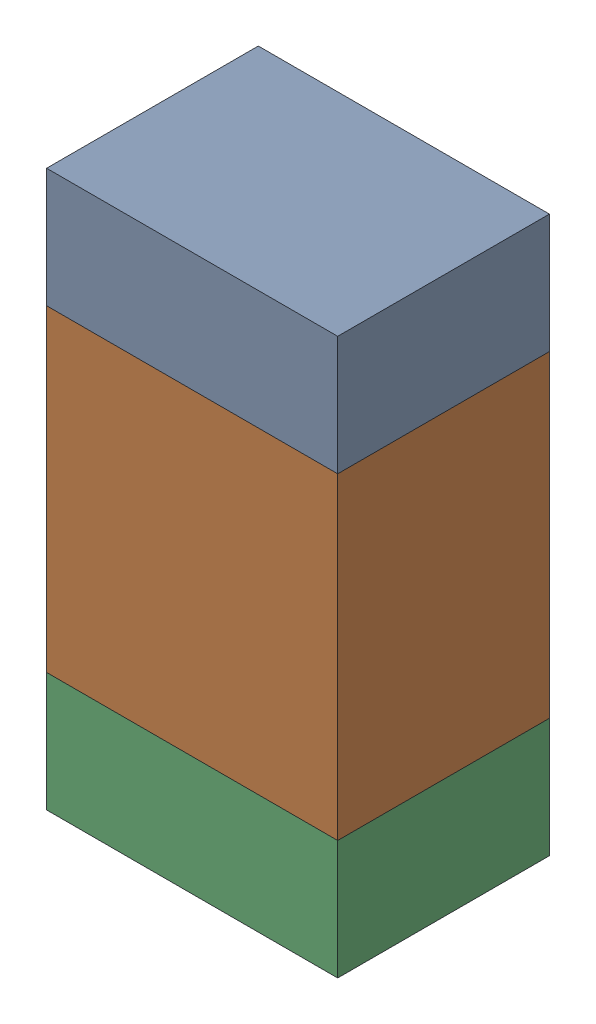
SolidWorks assembly R702PCB, configuration Default. Lengths in mm.
Overall size (0.55 1.05 0.4).
6 component instances, 2 part files, 0 mates.
Components (placement in the parent):
- 846483288-1: 846483288 [Default] at (116.7999 122.2124 -2.0638) size (0.55 0.22 0.4)
  - Extruded_12-1: Extruded_12 [Default] at origin size (0.55 0.22 0.4)
- 846483424-1: 846483424 [Default] at (116.7999 121.7999 -2.0638) size (0.55 0.6 0.4)
  - Extruded_13-1: Extruded_13 [Default] at origin size (0.55 0.6 0.4)
- 846483288-2: 846483288 [Default] at (116.7999 121.3874 -2.0638) size (0.55 0.22 0.4)
  - Extruded_12-1: Extruded_12 [Default] at origin size (0.55 0.22 0.4)
